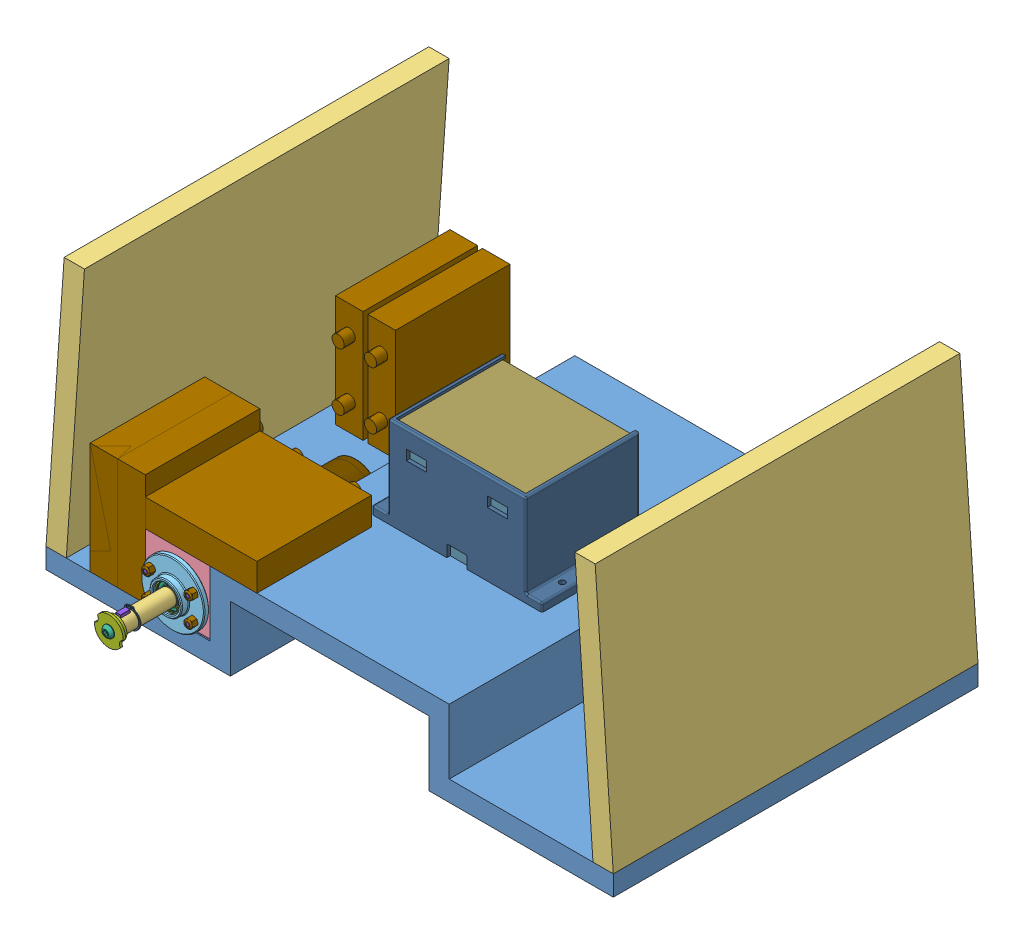
SolidWorks assembly ROVER_config2_discance_interbatteries, configuration Default. Lengths in mm.
Overall size (700 275 569.67).
75 component instances, 32 part files, 23 mates.
Components (placement in the parent):
- Plancher-1: Plancher [Default] at (-314.6501 422.5882 577.2661) size (700 105 450)
- 01-Anneau_separation-1: 01-Anneau_separation [Default] at (38.152 502.5882 794.9914) x (0.982803 0 -0.184657) z (-0.184657 0 -0.982803) size (228.6 10 228.6)
- Mur_largeur-1: Mur_largeur [Default] at (-314.6501 447.5882 577.2661) size (47.44 320 450)
- Mur_largeur-2: Mur_largeur [Default] at (385.3499 447.5882 1027.2661) x (-1 0 0) z (0 0 -1) size (47.44 320 450)
- PB2023-M054 DRIVETRAIN ASSEMBLY-1: PB2023-M054 DRIVETRAIN ASSEMBLY [Default] at (-152.1501 480.5882 991.7661) x (0 1 0) z (0 0 1) size (93.83 80 344.65)
  - A12220103_FRONT_BRACKET_ASSEMBLY-1: A12220103_FRONT_BRACKET_ASSEMBLY [Default] at origin size (86 80 534.65)
    - 12220105_SUPPORT_BRACKET-1: 12220105_SUPPORT_BRACKET [Default] at (-52 -128.9256 -192.9876) x (0 0 -1) z (1 0 0) size (160.65 80 80)
    - A12220101_FRONT_CASE_ASSEMBLY-1: A12220101_FRONT_CASE_ASSEMBLY [Default] at origin size (78 78 141.2)
      - 12220103_FRONT_HOUSING-1: 12220103_FRONT_HOUSING [Default] at (-52 141.0744 -192.9876) x (0 0 -1) z (1 0 0) size (60 78 78)
      - BALL BEARING-1: BALL BEARING [6656K203] at origin size (32 32 10)
      - BALL BEARING-2: BALL BEARING [6656K203] at (0 0 41) size (32 32 10)
      - Internal Retaining Ring (98455A129)-1: Internal Retaining Ring (98455A129) [98455A129] at (0.0361 0.7992 46) x (0.998982 -0.045107 0) z (0 0 1) size (34.4 33.81 1.2)
    - M6 x 20mm Steel Hex Head Screw (91310A333)-2: M6 x 20mm Steel Hex Head Screw (91310A333) [91310A333] at (-15.125 -26.1973 37.15) x (0 0 1) z (-0.44141 0.897306 0) size (24.4 11.55 10)
    - M6 x 1mm Steel Hex LockNut (90592A016)-1: M6 x 1mm Steel Hex LockNut (90592A016) [97260A101] at (15.125 -26.1973 41.85) x (0.928554 -0.371196 0) z (-0.371196 -0.928554 0) size (10 8.38 11.55)
    - 20MM External Retaining Ring (98541A123)-4: 20MM External Retaining Ring (98541A123) [98541A123] at (0 0 92.94) x (0 0 1) z (-0.186581 0.98244 0) size (1.2 25.1 22.76)
    - A12220110_FRONT_SHAFT_ASSEMBLY-1: A12220110_FRONT_SHAFT_ASSEMBLY [Default] at (1.7896 0 -19.01) x (0 -1 0) z (0 0 1) size (78 67.32 307.03)
      - A12220105_MOTOR_BRACKET_ASSEMBLY-1: A12220105_MOTOR_BRACKET_ASSEMBLY [Default] at origin size (78 67.32 280.24) (flexible)
        - 12220106_MOTOR_BRACKET-1: 12220106_MOTOR_BRACKET [Default] at (0 -2.2046 8.53) size (78 52.48 69.85)
        - 12220106-051 MiniCIM Motor Assembly-1: 12220106-051 MiniCIM Motor Assembly [Default] at origin size (64.01 67.32 218.97)
          - Gearbox Assembly-1: Gearbox Assembly [Default] at (34.0244 -12.4567 -92.7758) x (0 0 1) z (-1 0 0) size (123.35 56.32 44.45)
            - Output Housing-2: Output Housing [Default] at (64.8023 -0.856 18.2213) x (1 0 0) z (0 -1 0) size (75.7 44.45 56.32)
              - Housing-1: Housing [Default] at (19.8785 -6.4219 -11.5232) size (18.13 44.45 42)
              - Encoder.step-1: Encoder.step [Default] at (12.6785 15.8031 -11.5232) x (0 0 1) z (-1 0 0) size (56.32 42 21.21)
              - Gearbox_output_shaft-1: Gearbox_output_shaft [Default] at origin size (63.51 17 17)
            - Ring Gears-1: Ring Gears [Default] at (71.9808 10.6671 11.7994) x (1 0 0) z (0 -1 0) size (32.2 42 42)
            - Ring Gear Stage 3-1: Ring Gear Stage 3 [Default] at (59.2808 10.6671 11.7994) x (1 0 0) z (0 -1 0) size (28.65 42 42)
          - CIM Adaptor.step-1: CIM Adaptor.step [Default] at (0 -1.7896 -68.72) x (0 -1 0) z (-1 0 0) size (64.01 21.63 64.01)
          - Mini CIM-1: Mini CIM [Default] at (0 -1.7896 -80.245) x (0 0 -1) z (1 0 0) size (101.22 64.01 64.01)
          - 8-32 X 3IN LG - Black-Oxide Alloy Steel Socket Head Screw (90044A516)-1: 8-32 X 3IN LG - Black-Oxide Alloy Steel Socket Head Screw (90044A516) [90044A516] at (17.5 15.7104 -75.245) x (-0.08536 0.99635 0) z (0 0 -1) size (6.86 6.86 81.33)
          - 8-32 X 3IN LG - Black-Oxide Alloy Steel Socket Head Screw (90044A516)-3: 8-32 X 3IN LG - Black-Oxide Alloy Steel Socket Head Screw (90044A516) [90044A516] at (-17.5 -19.2896 -75.245) x (-0.242255 0.970213 0) z (0 0 -1) size (6.86 6.86 81.33)
        - 10-32 X 0.875IN LG - Black-Oxide Alloy Steel Socket Head Screw (91251A346)-1: 10-32 X 0.875IN LG - Black-Oxide Alloy Steel Socket Head Screw (91251A346) [91251A346] at (-17.9605 16.1709 6.1805) x (0.130335 0.99147 0) z (0 0 1) size (7.94 7.94 27.67)
        - 10-32 X 0.875IN LG - Black-Oxide Alloy Steel Socket Head Screw (91251A346)-2: 10-32 X 0.875IN LG - Black-Oxide Alloy Steel Socket Head Screw (91251A346) [91251A346] at (17.9605 -19.7501 6.1805) x (0.872398 0.488796 0) z (0 0 1) size (7.94 7.94 27.67)
      - PB2023-M005 ROTARY SHAFT-1: PB2023-M005 ROTARY SHAFT [Default] at (0 -1.7896 136.57) x (0 0 -1) z (1 0 0) size (126.56 25 25)
      - 12220110_MOTOR_KEY-1: 12220110_MOTOR_KEY [Default] at (0 5.1764 16.3975) size (3.17 4.76 26.16)
    - M6 x 20mm Steel Hex Head Screw (91310A333)-7: M6 x 20mm Steel Hex Head Screw (91310A333) [91310A333] at (15.125 -26.1973 37.15) x (0 0 1) z (0.78025 0.625468 0) size (24.4 11.55 10)
    - M6 x 20mm Steel Hex Head Screw (91310A333)-9: M6 x 20mm Steel Hex Head Screw (91310A333) [91310A333] at (15.125 26.1973 37.15) x (0 0 1) z (0.877007 0.480477 0) size (24.4 11.55 10)
    - M6 x 20mm Steel Hex Head Screw (91310A333)-11: M6 x 20mm Steel Hex Head Screw (91310A333) [91310A333] at (-15.0958 26.1466 37.15) x (0 0 1) z (0.947118 0.320887 0) size (24.4 11.55 10)
    - M6 x 1mm Steel Hex LockNut (90592A016)-7: M6 x 1mm Steel Hex LockNut (90592A016) [97260A101] at (-15.125 -26.1973 41.85) x (0.975663 -0.219276 0) z (-0.219276 -0.975663 0) size (10 8.38 11.55)
    - M6 x 1mm Steel Hex LockNut (90592A016)-9: M6 x 1mm Steel Hex LockNut (90592A016) [97260A101] at (-15.125 26.1973 41.85) x (0.995642 -0.093258 0) z (-0.093258 -0.995642 0) size (10 8.38 11.55)
    - M6 x 1mm Steel Hex LockNut (90592A016)-11: M6 x 1mm Steel Hex LockNut (90592A016) [97260A101] at (15.2049 26.151 41.85) x (1 -0.000046 0) z (-0.000046 -1 0) size (10 8.38 11.55)
  - M6 x 25mm Steel Socket Head Screw (91290A330)-1: M6 x 25mm Steel Socket Head Screw (91290A330) [91290A330] at (-31.155 30 -64.48) x (0 -0.901175 -0.433456) z (1 0 0) size (10 10 31.46)
  - M6 x 25mm Steel Socket Head Screw (91290A330)-2: M6 x 25mm Steel Socket Head Screw (91290A330) [91290A330] at (-31.155 -30 -64.48) x (0 -0.15786 -0.987461) z (1 0 0) size (10 10 31.46)
  - M6 x 1mm Steel Hex LockNut (90592A016)-1: M6 x 1mm Steel Hex LockNut (90592A016) [97260A101] at (-33 -30 -64.48) x (0 0.608626 0.793457) z (0 -0.793457 0.608626) size (10 8.38 11.55)
  - M6 x 1mm Steel Hex LockNut (90592A016)-2: M6 x 1mm Steel Hex LockNut (90592A016) [97260A101] at (-33 30 -64.48) x (0 -0.994883 0.101031) z (0 -0.101031 -0.994883) size (10 8.38 11.55)
  - M8 X 20MM - 18-8 Stainless Steel Button Head Hex Drive Screws (97763A444)-1: M8 X 20MM - 18-8 Stainless Steel Button Head Hex Drive Screws (97763A444) [97763A444] at (0 0 124.825) x (0.999813 0.019347 0) z (0 0 1) size (14 14 25.15)
  - PB2023-M006 WHEEL END CAP CUSTOM WASHER-1: PB2023-M006 WHEEL END CAP CUSTOM WASHER [Default] at (0 0 117.56) x (0 0 -1) z (-0.345262 -0.938506 0) size (8.5 35.5 34.05)
  - 98870A743_Machine Key-1: 98870A743_Machine Key [98870A743] at (10 0 103.06) size (6 6 12)
- 02-Batterie-2: 02-Batterie [Default] at (-226.1501 447.5882 1027.2661) x (0 1 0) z (-1 0 0) size (137.7 155.1 34)
- 02-Batterie-3: 02-Batterie [Default] at (-260.1501 447.5882 1027.2661) x (0 1 0) z (-1 0 0) size (137.7 155.1 34)
- A12220113_ELECTRICAL_CONTROL_BOX-1: A12220113_ELECTRICAL_CONTROL_BOX [Default] at (-17.8776 469.5906 631.9499) size (210 113.22 141.5)
  - 12220118_ELECTRICAL_BOX-1: 12220118_ELECTRICAL_BOX [Default] at (-29.7877 57.9976 190.2575) size (210 112.5 140)
  - 12220120_ELECTRICAL_BOX_OPENING_SLOT-1: 12220120_ELECTRICAL_BOX_OPENING_SLOT [Default] at (55.2123 57.9976 102.7575) x (-1 0 0) z (0 0 -1) size (30.6 54.5 6.5)
  - 12220119_ACRYLIC_SHEET-1: 12220119_ACRYLIC_SHEET [Default] at (55.2123 163.7976 170.2575) x (0 0 -1) z (1 0 0) size (135 2.8 165)
  - A12220112_SLOT_WITH_BRUSH-1: A12220112_SLOT_WITH_BRUSH [Default] at (-16.3066 139.0751 243.5929) x (0 0 -1) z (1 0 0) size (9.7 29.24 29.5)
    - 12220122_SLOT-1: 12220122_SLOT [Default] at (12.7854 19.2475 6.7689) size (9.7 11.4 29.5)
    - 12220121_BRUSH-1: 12220121_BRUSH [74405T911] at (9.9542 14.2475 21.5369) size (4.76 25.4 29.46)
  - A12220112_SLOT_WITH_BRUSH-2: A12220112_SLOT_WITH_BRUSH [Default] at (83.6934 139.0751 243.5929) x (0 0 -1) z (1 0 0) size (9.7 29.24 29.5)
    - 12220122_SLOT-1: 12220122_SLOT [Default] at (12.7854 19.2475 6.7689) size (9.7 11.4 29.5)
    - 12220121_BRUSH-1: 12220121_BRUSH [74405T911] at (9.9542 14.2475 21.5369) size (4.76 25.4 29.46)
  - A12220112_SLOT_WITH_BRUSH-3: A12220112_SLOT_WITH_BRUSH [Default] at (33.6934 62.8751 243.5929) x (0 0 -1) z (1 0 0) size (9.7 29.24 29.5)
    - 12220122_SLOT-1: 12220122_SLOT [Default] at (12.7854 19.2475 6.7689) size (9.7 11.4 29.5)
    - 12220121_BRUSH-1: 12220121_BRUSH [74405T911] at (9.9542 14.2475 21.5369) size (4.76 25.4 29.46)
  - A12220112_SLOT_WITH_BRUSH-4: A12220112_SLOT_WITH_BRUSH [Default] at (26.7312 139.0751 96.9221) x (0 0 1) z (-1 0 0) size (9.7 29.24 29.5)
    - 12220122_SLOT-1: 12220122_SLOT [Default] at (12.7854 19.2475 6.7689) size (9.7 11.4 29.5)
    - 12220121_BRUSH-1: 12220121_BRUSH [74405T911] at (9.9542 14.2475 21.5369) size (4.76 25.4 29.46)
  - A12220112_SLOT_WITH_BRUSH-5: A12220112_SLOT_WITH_BRUSH [Default] at (126.7312 139.0751 96.9221) x (0 0 1) z (-1 0 0) size (9.7 29.24 29.5)
    - 12220122_SLOT-1: 12220122_SLOT [Default] at (12.7854 19.2475 6.7689) size (9.7 11.4 29.5)
    - 12220121_BRUSH-1: 12220121_BRUSH [74405T911] at (9.9542 14.2475 21.5369) size (4.76 25.4 29.46)
  - A12220112_SLOT_WITH_BRUSH-6: A12220112_SLOT_WITH_BRUSH [Default] at (76.7312 117.8751 96.9221) x (0 0 1) z (-1 0 0) size (9.7 29.24 29.5)
    - 12220122_SLOT-1: 12220122_SLOT [Default] at (12.7854 19.2475 6.7689) size (9.7 11.4 29.5)
    - 12220121_BRUSH-1: 12220121_BRUSH [74405T911] at (9.9542 14.2475 21.5369) size (4.76 25.4 29.46)
- 02-Batterie-5: 02-Batterie [Default] at (-192.1501 447.5882 577.2661) x (0 1 0) z (1 0 0) size (137.7 155.1 34)
- 02-Batterie-6: 02-Batterie [Default] at (-232.1501 447.5882 577.2661) x (0 1 0) z (1 0 0) size (137.7 155.1 34)
- 02-Batterie-7: 02-Batterie [Default] at (-260.1501 447.5882 1027.2661) x (0 1 0) z (-1 0 0) size (137.7 155.1 34)
- 02-Batterie-8: 02-Batterie [Default] at (-54.4501 527.5882 1027.2661) x (-1 0 0) z (0 -1 0) size (137.7 155.1 34)
Mates (geometry in assembly coordinates):
- Coincident5: coincident anti-aligned: plane of Plancher-1 through (-87.1501 502.5882 1027.2661) normal (0 -1 0); plane of 01-Anneau_separation-1 through (38.152 502.5882 794.9914) normal (0 1 0)
- Coincident6: coincident anti-aligned: plane of Plancher-1 through (-314.6501 447.5882 1027.2661) normal (0 1 0); plane of Mur_largeur-1 through (-289.5891 447.5882 1027.2661) normal (0 -1 0)
- Coincident7: coincident aligned: plane of Plancher-1 through (-314.6501 422.5882 1027.2661) normal (0 0 1); plane of Mur_largeur-1 through (-314.6501 447.5882 1027.2661) normal (0 0 1)
- Coincident8: coincident aligned: line of Plancher-1 through (-314.6501 447.5882 1027.2661) axis (0 0 -1); line of Mur_largeur-1 through (-314.6501 447.5882 1027.2661) axis (0 0 -1)
- Coincident9: coincident anti-aligned: plane of Plancher-1 through (385.3499 447.5882 1027.2661) normal (0 1 0); plane of Mur_largeur-2 through (360.2888 447.5882 577.2661) normal (0 -1 0)
- Coincident10: coincident aligned: plane of Plancher-1 through (-314.6501 422.5882 1027.2661) normal (0 0 1); plane of Mur_largeur-2 through (385.3499 447.5882 1027.2661) normal (0 0 1)
- Coincident11: coincident anti-aligned: line of Plancher-1 through (385.3499 447.5882 1027.2661) axis (0 0 -1); line of Mur_largeur-2 through (385.3499 447.5882 577.2661) axis (0 0 1)
- Coincident12: coincident anti-aligned: plane of Plancher-1 through (-314.6501 447.5882 1027.2661) normal (0 1 0); plane of PB2023-M054 DRIVETRAIN ASSEMBLY-1/A12220103_FRONT_BRACKET_ASSEMBLY-1/12220105_SUPPORT_BRACKET-1 through (-152.1501 447.5882 1027.2661) normal (0 -1 0)
- Coincident13: coincident aligned: plane of Plancher-1 through (-314.6501 422.5882 1027.2661) normal (0 0 1); plane of PB2023-M054 DRIVETRAIN ASSEMBLY-1/A12220103_FRONT_BRACKET_ASSEMBLY-1/12220105_SUPPORT_BRACKET-1 through (-192.1501 453.9382 1027.2661) normal (0 0 1)
- Coincident14: coincident anti-aligned: plane of Plancher-1 through (-112.1501 447.5882 1027.2661) normal (-1 0 0); plane of PB2023-M054 DRIVETRAIN ASSEMBLY-1/A12220103_FRONT_BRACKET_ASSEMBLY-1/12220105_SUPPORT_BRACKET-1 through (-112.1501 453.9382 1027.2661) normal (1 0 0)
- Coincident15: coincident anti-aligned: plane of Plancher-1 through (-314.6501 447.5882 1027.2661) normal (0 1 0); plane of 02-Batterie-2 through (-226.1501 447.5882 885.9661) normal (0 -1 0)
- Coincident16: coincident anti-aligned: plane of PB2023-M054 DRIVETRAIN ASSEMBLY-1/A12220103_FRONT_BRACKET_ASSEMBLY-1/12220105_SUPPORT_BRACKET-1 through (-192.1501 453.9382 831.6161) normal (-1 0 0); plane of 02-Batterie-2 through (-192.1501 447.5882 885.9661) normal (1 0 0)
- Coincident17: coincident aligned: plane of Plancher-1 through (-314.6501 422.5882 1027.2661) normal (0 0 1); plane of 02-Batterie-2 through (-226.1501 447.5882 1027.2661) normal (0 0 1)
- Coincident18: coincident anti-aligned: plane of 02-Batterie-2 through (-226.1501 447.5882 885.9661) normal (-1 0 0); plane of 02-Batterie-3 through (-226.1501 447.5882 885.9661) normal (1 0 0)
- Coincident19: coincident aligned: plane of 02-Batterie-2 through (-226.1501 447.5882 1027.2661) normal (0 0 1); plane of 02-Batterie-3 through (-260.1501 447.5882 1027.2661) normal (0 0 1)
- Coincident20: coincident anti-aligned: plane of Plancher-1 through (-314.6501 447.5882 1027.2661) normal (0 1 0); plane of 02-Batterie-3 through (-260.1501 447.5882 885.9661) normal (0 -1 0)
- Coincident21: coincident anti-aligned: plane of Plancher-1 through (-112.1501 527.5882 1027.2661) normal (0 1 0); plane of A12220113_ELECTRICAL_CONTROL_BOX-1/12220118_ELECTRICAL_BOX-1 through (122.3347 527.5882 822.2073) normal (0 -1 0)
- Coincident22: coincident aligned: plane of 02-Batterie-2 through (-192.1501 447.5882 885.9661) normal (1 0 0); plane of 02-Batterie-5 through (-192.1501 447.5882 718.5661) normal (1 0 0)
- Coincident23: coincident anti-aligned: plane of Plancher-1 through (-314.6501 447.5882 1027.2661) normal (0 1 0); plane of 02-Batterie-5 through (-192.1501 447.5882 718.5661) normal (0 -1 0)
- Coincident24: coincident aligned: plane of Plancher-1 through (-314.6501 422.5882 577.2661) normal (0 0 -1); plane of 02-Batterie-5 through (-192.1501 447.5882 577.2661) normal (0 0 -1)
- Coincident28: coincident anti-aligned: plane of 02-Batterie-2 through (-192.1501 447.5882 885.9661) normal (1 0 0); plane of 02-Batterie-8 through (-192.1501 527.5882 885.9661) normal (-1 0 0)
- Coincident29: coincident anti-aligned: plane of Plancher-1 through (-112.1501 527.5882 1027.2661) normal (0 1 0); plane of 02-Batterie-8 through (-54.4501 527.5882 885.9661) normal (0 -1 0)
- Coincident30: coincident aligned: plane of 02-Batterie-2 through (-226.1501 447.5882 1027.2661) normal (0 0 1); plane of 02-Batterie-8 through (-54.4501 527.5882 1027.2661) normal (0 0 1)
